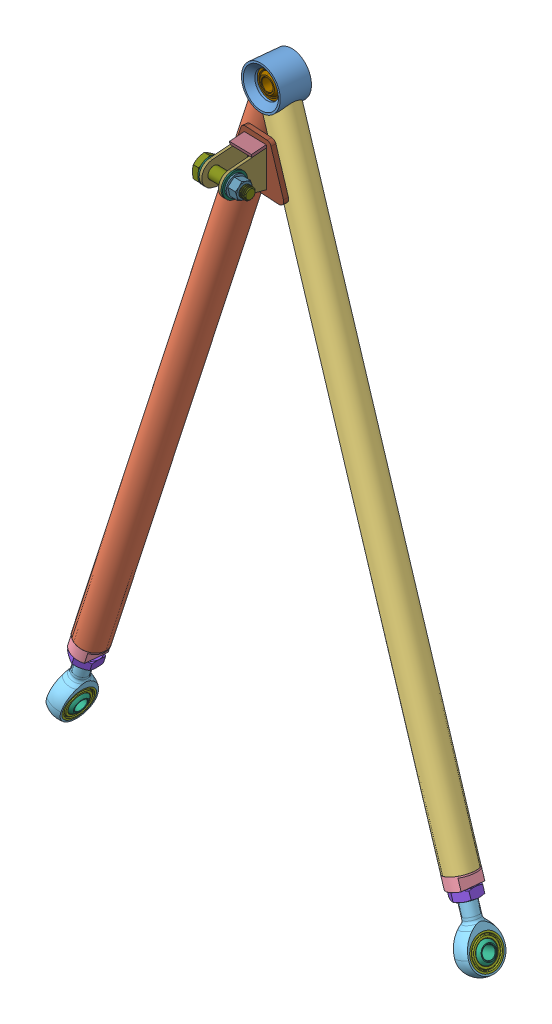
SolidWorks assembly 24-SU-22-000, configuration Default. Lengths in mm.
Overall size (260.55 364.24 46.28).
25 component instances, 17 part files, 32 mates.
Components (placement in the parent):
- 24-SU-00-001-1: 24-SU-00-001 [Default<As Machined>] at origin (hidden)
- 24-SU-20-003-1: 24-SU-20-003 [Default] at (0 523.875 106.68) x (0.67833 -0.731484 0.06928) z (0.059926 -0.038899 -0.997445) size (22.23 22.23 15.88)
- 24-SU-22-001-1: 24-SU-22-001 [Default<As Machined>] at origin size (102.36 301.06 22.5)
- 24-SU-22-002-1: 24-SU-22-002 [Default<As Machined>] at origin size (125.99 298.6 34.57)
- 24-SU-25-004-1: 24-SU-25-004 [5_16 24] at (117.9912 224.5191 125.4433) x (-0.366073 0.928764 -0.058214) z (0.928655 0.368626 0.041417) size (21.46 15.88 15.88)
- 24-SU-25-004-2: 24-SU-25-004 [5_16 24] at (-93.2953 220.6653 112.8997) x (0.294029 0.955595 -0.019602) z (0.953916 -0.292103 0.068702) size (21.46 15.88 15.88)
- ASM-4T-1: ASM-4T [Default] at (115.6713 230.405 125.0744) x (0.059926 -0.038899 -0.997445) z (0.366073 -0.928764 0.058214) size (20.56 20.47 49.91)
  - ASM-4T Rod End Body-1: ASM-4T Rod End Body [Default] at origin size (20.56 20.47 49.91)
  - ASM-4T Ball Bearing-1: ASM-4T Ball Bearing [Default] at origin size (13.49 13.49 13.49)
  - ASM-4T Staked Bearing-1: ASM-4T Staked Bearing [Default] at origin size (16.89 8.56 16.89)
- ASM-4T-2: ASM-4T [Default] at (-91.4319 226.7212 112.7755) x (0.059926 -0.038899 -0.997445) z (-0.294029 -0.955595 0.019602) size (20.56 20.47 49.91)
  - ASM-4T Rod End Body-1: ASM-4T Rod End Body [Default] at origin size (20.56 20.47 49.91)
  - ASM-4T Ball Bearing-1: ASM-4T Ball Bearing [Default] at origin size (13.49 13.49 13.49)
  - ASM-4T Staked Bearing-1: ASM-4T Staked Bearing [Default] at origin size (16.89 8.56 16.89)
- AN5_JamNut-1: AN5_JamNut [93839A810] at (-95.8625 212.3218 113.0708) x (0.955792 -0.294029 0.002947) z (0.002947 0.019602 0.999804) size (12.7 4.76 14.66)
- AN5_JamNut-2: AN5_JamNut [93839A810] at (121.1875 216.4099 125.9516) x (0.930521 0.366073 -0.011049) z (-0.011049 0.058214 0.998243) size (12.7 4.76 14.66)
- MIB-4T-1: MIB-4T [Default] at (-0.0015 523.876 106.7053) x (0.996543 0.059926 0.057535) z (0.057535 -0.997445 0.042356) size (15.48 9.53 15.48)
- 99142A370_BLACK-FINISH STEEL INTERNAL RETAINING RING-1: 99142A370_BLACK-FINISH STEEL INTERNAL RETAINING RING [99142A370] at (0.2154 523.7352 103.0951) x (0.996543 0.059926 0.057535) z (0.057535 -0.997445 0.042356) size (17.63 0.89 16.8)
- 24-SU-22-003-1: 24-SU-22-003 [Default] at origin size (31.92 25.52 4.91)
- 24-SU-22-004-1: 24-SU-22-004 [Default] at origin size (14.36 19.31 24.24)
- 24-SU-22-005-1: 24-SU-22-005 [Default] at origin size (13.01 3.05 8.48)
- AN4_KNut-1: AN4_KNut [Default] at (9.3621 493.1363 135.8085) x (0.048723 0.20736 -0.977051) z (0.997473 0.040545 0.058346) size (10.39 10.39 5.38)
- AN4_Washer-1: AN4_Washer [Thin] at (6.6765 493.0271 135.6514) x (-0.061542 0.903424 0.424309) z (-0.997473 -0.040545 -0.058346) size (12.7 12.7 0.81)
- AN4_Washer-2: AN4_Washer [Thin] at (-7.4862 492.4514 134.8229) x (0.059899 -0.038213 -0.997473) z (0.997473 0.040545 0.058346) size (12.7 12.7 0.81)
- AN4_Bolt-1: AN4_Bolt [-7] at (-11.4386 492.2908 134.5917) x (0.059899 -0.038213 -0.997473) z (0.997473 0.040545 0.058346) size (11.11 12.83 27)
Mates (geometry in assembly coordinates):
- Coincident2: coordinate: point of 23-SU-00-001-1
- Coincident4: coincident: unknown of ?; unknown of 24-SU-20-003-1
- Perpendicular2: perpendicular: line of 23-SU-00-001-1 through (-103.0975 188.8082 113.5532) axis (0.294029 0.955595 -0.019602); line of 23-SU-20-003-1 through (0.2154 523.7352 103.0951) axis (-0.059926 0.038899 0.997445)
- Perpendicular3: perpendicular: line of 23-SU-00-001-1 through (0 523.875 106.68) axis (0.366073 -0.928764 0.058214); line of 23-SU-20-003-1 through (0.2154 523.7352 103.0951) axis (-0.059926 0.038899 0.997445)
- Concentric1: concentric aligned: cylinder of 23-SU-22-002-1 through (4.068 513.5541 107.3269) axis (0.366073 -0.928764 0.058214) radius 7.0485; cylinder of 23-SU-25-004-1 through (112.4588 238.5556 124.5635) axis (0.366073 -0.928764 0.058214) radius 7.0485
- Coincident5: coincident anti-aligned: plane of 23-SU-22-002-1 through (117.9912 224.5191 125.4433) normal (0.366073 -0.928764 0.058214); plane of 23-SU-25-004-1 through (117.9912 224.5191 125.4433) normal (-0.366073 0.928764 -0.058214)
- Perpendicular4: perpendicular: plane of 23-SU-20-003-1 through (-0.4757 524.1838 114.5972) normal (-0.059926 0.038899 0.997445); plane of 23-SU-25-004-1 through (125.5024 220.2822 119.6935) normal (0.928655 0.368626 0.041417)
- Concentric2: concentric aligned: cylinder of 23-SU-22-001-1 through (-3.2674 513.2559 106.8978) axis (-0.294029 -0.955595 0.019602) radius 7.0485; cylinder of 23-SU-25-004-2 through (-88.8516 235.1073 112.6034) axis (-0.294029 -0.955595 0.019602) radius 7.0485
- Coincident7: coincident anti-aligned: plane of 23-SU-22-001-1 through (-93.2953 220.6653 112.8997) normal (-0.294029 -0.955595 0.019602); plane of 23-SU-25-004-2 through (-93.2953 220.6653 112.8997) normal (0.294029 0.955595 -0.019602)
- Perpendicular5: perpendicular: plane of 23-SU-20-003-1 through (-0.4757 524.1838 114.5972) normal (-0.059926 0.038899 0.997445); plane of 23-SU-25-004-2 through (-89.8451 212.8386 107.0459) normal (0.953916 -0.292103 0.068702)
- Concentric3: concentric anti-aligned: cylinder of 23-SU-22-002-1 through (4.068 513.5541 107.3269) axis (0.366073 -0.928764 0.058214) radius 7.0485; cylinder of ASM-4T-1/ASM-4T Rod End Body-1 through (120.2874 218.6935 125.8085) axis (-0.366073 0.928764 -0.058214) radius 3.9688
- Concentric4: concentric: cylinder of ASM-4T-1/ASM-4T Ball Bearing-1 through (130.1952 193.5565 127.384) axis (0.928655 0.368626 0.041417) radius 3.175; unknown of ASM-4T-1/ASM-4T Ball Bearing-1
- Perpendicular9: perpendicular: plane of 23-SU-20-003-1 through (-0.4757 524.1838 114.5972) normal (-0.059926 0.038899 0.997445); plane of ASM-4T-1/ASM-4T Rod End Body-1 through (126.834 191.5806 116.9967) normal (-0.928655 -0.368626 -0.041417)
- Concentric5: concentric anti-aligned: cylinder of 23-SU-22-001-1 through (-3.2674 513.2559 106.8978) axis (-0.294029 -0.955595 0.019602) radius 7.0485; cylinder of ASM-4T-2/ASM-4T Rod End Body-1 through (-95.1396 214.6713 113.0226) axis (0.294029 0.955595 -0.019602) radius 3.9688
- Concentric6: concentric: cylinder of ASM-4T-2/ASM-4T Ball Bearing-1 through (-103.0975 188.8082 113.5532) axis (0.953916 -0.292103 0.068702) radius 3.175; unknown of ASM-4T-2/ASM-4T Ball Bearing-1
- Perpendicular10: perpendicular: plane of 23-SU-20-003-1 through (-0.4757 524.1838 114.5972) normal (-0.059926 0.038899 0.997445); plane of ASM-4T-2/ASM-4T Rod End Body-1 through (-106.5667 189.6602 103.0491) normal (-0.953916 0.292103 -0.068702)
- Concentric7: concentric anti-aligned: cylinder of 23-SU-22-001-1 through (-3.2674 513.2559 106.8978) axis (-0.294029 -0.955595 0.019602) radius 7.0485; cylinder of AN5_JamNut-1 through (-95.1624 214.5973 113.0242) axis (0.294029 0.955595 -0.019602) radius 3.4544
- Coincident14: coincident anti-aligned: plane of 23-SU-25-004-2 through (-95.1624 214.5973 113.0242) normal (-0.294029 -0.955595 0.019602); plane of AN5_JamNut-1 through (-101.2424 216.3925 109.34) normal (0.294029 0.955595 -0.019602)
- Concentric8: concentric anti-aligned: cylinder of 23-SU-22-002-1 through (4.068 513.5541 107.3269) axis (0.366073 -0.928764 0.058214) radius 7.0485; cylinder of AN5_JamNut-2 through (120.3158 218.6215 125.813) axis (-0.366073 0.928764 -0.058214) radius 3.4544
- Coincident15: coincident anti-aligned: plane of 23-SU-25-004-1 through (120.3158 218.6215 125.813) normal (0.366073 -0.928764 0.058214); plane of AN5_JamNut-2 through (114.4475 216.0835 122.2234) normal (-0.366073 0.928764 -0.058214)
- Concentric9: concentric anti-aligned: cylinder of 23-SU-20-003-1 through (-0.4757 524.1838 114.5972) axis (-0.059926 0.038899 0.997445) radius 7.7318; cylinder of MIB-4T-1 through (-0.0015 523.876 106.7053) axis (0.059926 -0.038899 -0.997445) radius 7.7394
- Coincident16: coincident anti-aligned: plane of 23-SU-20-003-1 through (-0.2154 524.0148 110.2649) normal (0.059926 -0.038899 -0.997445); plane of MIB-4T-1 through (-0.5953 530.6005 109.9853) normal (-0.059926 0.038899 0.997445)
- Concentric10: concentric aligned: cylinder of 23-SU-20-003-1 through (-0.4757 524.1838 114.5972) axis (-0.059926 0.038899 0.997445) radius 8.4455; cylinder of 99142A370_BLACK-FINISH STEEL INTERNAL RETAINING RING-1 through (0.2687 523.7006 102.2084) axis (-0.059926 0.038899 0.997445) radius 8.8138
- Coincident17: coincident anti-aligned: plane of 23-SU-20-003-1 through (0.2154 523.7352 103.0951) normal (0.059926 -0.038899 -0.997445); plane of 99142A370_BLACK-FINISH STEEL INTERNAL RETAINING RING-1 through (4.9723 518.437 103.5875) normal (-0.059926 0.038899 0.997445)
- Coincident18: coincident anti-aligned: plane of 23-SU-22-004-1 through (5.8658 492.9941 135.6039) normal (0.997473 0.040545 0.058346); plane of AN4_Washer-1 through (5.8658 492.9941 135.6039) normal (-0.997473 -0.040545 -0.058346)
- Concentric11: concentric anti-aligned: cylinder of 23-SU-22-004-1 through (5.8658 492.9941 135.6039) axis (-0.997473 -0.040545 -0.058346) radius 3.2639; cylinder of AN4_Washer-1 through (5.8658 492.9941 135.6039) axis (0.997473 0.040545 0.058346) radius 3.3528
- Coincident19: coincident anti-aligned: plane of 23-SU-22-004-1 through (-6.6754 492.4844 134.8704) normal (-0.997473 -0.040545 -0.058346); plane of AN4_Washer-2 through (-6.6754 492.4844 134.8704) normal (0.997473 0.040545 0.058346)
- Concentric12: concentric aligned: cylinder of 23-SU-22-004-1 through (5.8658 492.9941 135.6039) axis (-0.997473 -0.040545 -0.058346) radius 3.2639; cylinder of AN4_Washer-2 through (-6.6754 492.4844 134.8704) axis (-0.997473 -0.040545 -0.058346) radius 3.3528
- Concentric13: concentric anti-aligned: cylinder of 23-SU-22-004-1 through (5.8658 492.9941 135.6039) axis (-0.997473 -0.040545 -0.058346) radius 3.2639; cylinder of AN4_KNut-1 through (12.0477 493.2454 135.9655) axis (0.997473 0.040545 0.058346) radius 2.7051
- Coincident20: coincident anti-aligned: plane of AN4_KNut-1 through (6.9884 491.6104 131.3043) normal (-0.997473 -0.040545 -0.058346); plane of AN4_Washer-1 through (6.6765 493.0271 135.6514) normal (0.997473 0.040545 0.058346)
- Concentric14: concentric aligned: cylinder of AN4_Bolt-1 through (3.5982 492.902 135.4713) axis (-0.997473 -0.040545 -0.058346) radius 3.175; cylinder of 23-SU-22-004-1 through (5.8658 492.9941 135.6039) axis (-0.997473 -0.040545 -0.058346) radius 3.2639
- Coincident21: coincident anti-aligned: plane of AN4_Washer-2 through (-7.4862 492.4514 134.8229) normal (-0.997473 -0.040545 -0.058346); plane of AN4_Bolt-1 through (-6.8205 492.0268 123.7385) normal (0.997473 0.040545 0.058346)
